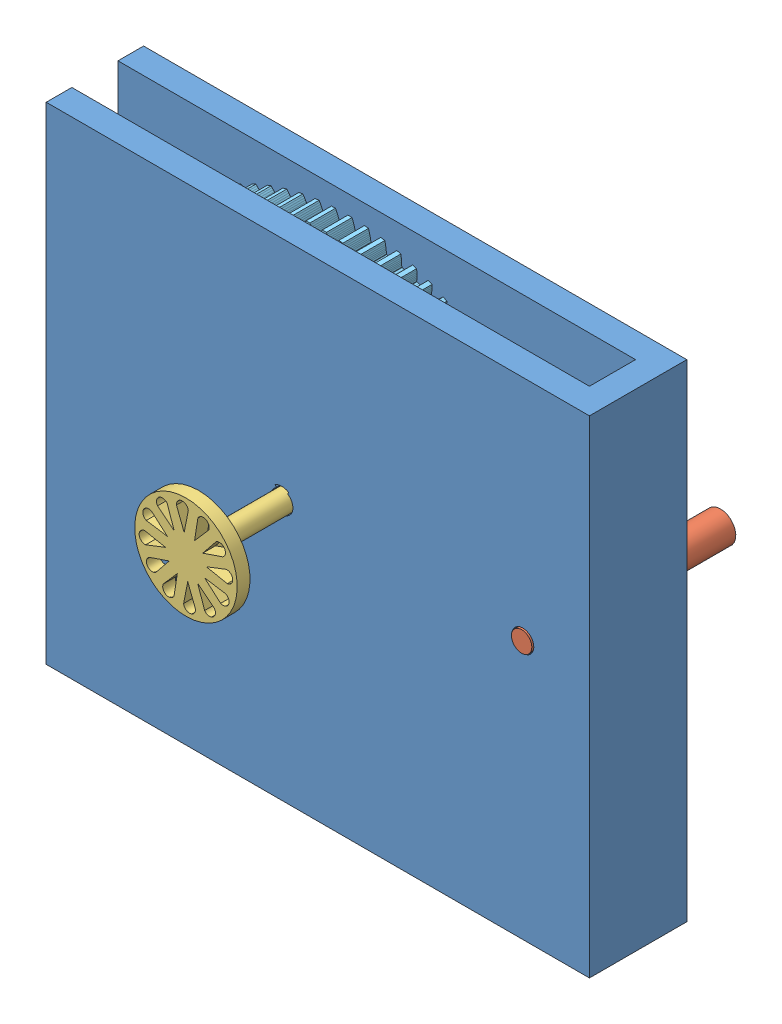
SolidWorks assembly AsamblatFinal, configuration Default. Lengths in mm.
Overall size (106 95 57.3).
5 component instances, 5 part files, 6 mates.
Components (placement in the parent):
- CutieBuna-1: CutieBuna [Default] at (6.0544 54.1092 81.6467) size (106 95 19)
- PanaBuna1-1: PanaBuna1 [Default] at (78.908 65.036 86.8846) x (-0.997823 -0.065945 0) z (0 0 -1) size (6 6 38.8)
- PanaBuna2-1: PanaBuna2 [Default] at (31.908 65.036 68.0806) x (0.996138 0.087804 0) z (0 0 1) size (20 20 37.3)
- Roata11-1: Roata11 [Default] at (78.908 65.036 80.7698) x (-0.999996 -0.002939 0) z (0 0 -1) size (12 11.58 5)
- Roata22-1: Roata22 [Default] at (-14.5631 63.3967 74.2854) x (0.999378 0.035254 0) z (0 0 1) size (84.98 85 5)
Mates (geometry in assembly coordinates):
- Concentric1: concentric anti-aligned: cylinder of PanaBuna1-1 through (78.908 65.036 73.0846) axis (0 0 1) radius 2.35; cylinder of Roata11-1 through (78.908 65.036 89.7698) axis (0 0 -1) radius 2.4
- Concentric2: concentric anti-aligned: cylinder of CutieBuna-1 through (78.908 65.036 86.6467) axis (0 0 -1) radius 2.15; cylinder of PanaBuna1-1 through (78.908 65.036 81.6846) axis (0 0 1) radius 2
- Concentric3: concentric anti-aligned: cylinder of PanaBuna2-1 through (31.908 65.036 81.8806) axis (0 0 -1) radius 2.35; cylinder of Roata22-1 through (31.908 65.036 69.2854) axis (0 0 1) radius 2.4
- Concentric5: concentric aligned: cylinder of CutieBuna-1 through (31.908 65.036 86.6467) axis (0 0 -1) radius 2.15; cylinder of PanaBuna2-1 through (31.908 65.036 73.2806) axis (0 0 -1) radius 2
- Concentric6: concentric anti-aligned: circle of CutieBuna-1; circle of PanaBuna2-1
- Concentric7: concentric anti-aligned: circle of CutieBuna-1; circle of PanaBuna2-1
